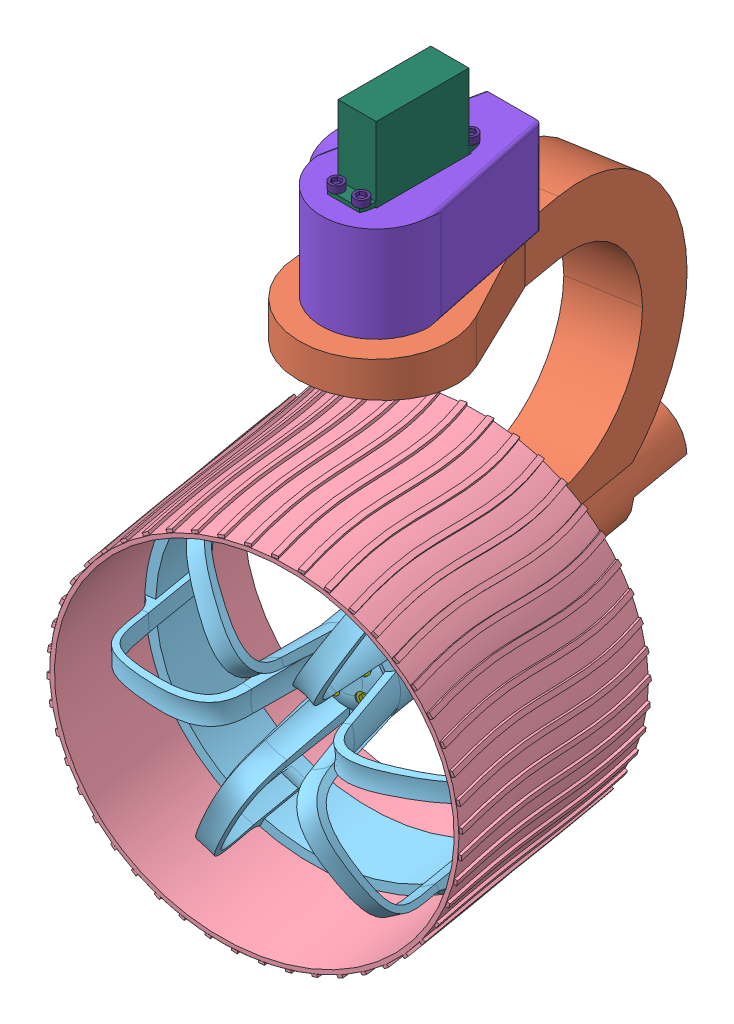
SolidWorks assembly Wheel + connector(right,front), configuration Default. Lengths in mm.
Overall size (148.6 246.82 187.43).
30 component instances, 17 part files, 54 mates.
Components (placement in the parent):
- Wheel motor(RH)-1: Wheel motor(RH) [Default] at (-243.8656 -139.499 44.1514) x (-0.875631 0.459235 0.149579) z (0.168385 0 0.985721) size (25 25 73.38)
- Wheel connector(right,front)-1: Wheel connector(right,front) [right frint (mirror)] at (-329.4884 -84.5922 3.3571) x (-0.168385 0 -0.985721) z (0.985721 0 -0.168385) size (150.03 127 55.1)
- connector to wheel(RH)-1: connector to wheel(RH) [Default] at (-239.521 -143.7607 82.6694) x (0.719368 -0.683673 -0.122885) z (-0.168385 0 -0.985721) size (25 25 12.5)
- Wheel-1: Wheel [Default] at (-237.5004 -143.7607 94.498) x (-0.032143 0.999468 0.005491) z (0.168385 0 0.985721) size (132 132 85)
  - Wheel Part-1-1: Wheel Part-1 [Default] at origin size (132 132 85)
  - Wheel Part-2-1: Wheel Part-2 [Default] at (0 0 -2) size (127 128.13 59.75)
- M3 nut-1: M3 nut [Default] at (-236.6979 -138.6522 70.7742) x (0.22394 0.973852 -0.038254) z (0.168385 0 0.985721) size (5 6.35 2.75)
- M3 nut-2: M3 nut [Default] at (-246.4509 -138.975 72.4402) x (0.673911 0.729788 -0.11512) z (0.168385 0 0.985721) size (5 6.35 2.75)
- M3 nut-3: M3 nut [Default] at (-236.3797 -148.5464 70.7198) x (0.673911 0.729788 -0.11512) z (0.168385 0 0.985721) size (5 6.35 2.75)
- M3 nut-4: M3 nut [Default] at (-246.1327 -148.8692 72.3858) x (0.943308 0.290179 -0.161139) z (0.168385 0 0.985721) size (5 6.35 2.75)
- M3 bolt for wheels(RH)-1: M3 bolt for wheels(RH) [Default] at (-242.6622 -138.975 94.6189) x (-0.910538 -0.383049 0.155542) z (-0.168385 0 -0.985721) size (5 5 25.25)
- M3 bolt for wheels(RH)-2: M3 bolt for wheels(RH) [Default] at (-242.344 -148.8692 94.5646) x (-0.910538 -0.383049 0.155542) z (-0.168385 0 -0.985721) size (5 5 25.25)
- M3 bolt for wheels(RH)-3: M3 bolt for wheels(RH) [Default] at (-232.5911 -148.5464 92.8985) x (-0.910538 -0.383049 0.155542) z (-0.168385 0 -0.985721) size (5 5 25.25)
- M3 bolt for wheels(RH)-4: M3 bolt for wheels(RH) [Default] at (-232.9093 -138.6522 92.9529) x (-0.910538 -0.383049 0.155542) z (-0.168385 0 -0.985721) size (5 5 25.25)
- Steering connector(right,front)-1: Steering connector(right,front) [RH] at (-182.0258 -27.059 85.0059) x (0 0 -1) z (1 0 0) size (70 36.07 55.83)
- Washer(M6)-1: Washer(M6) [Default] at (-237.0258 -27.559 85.0059) size (8.76 0.5 8.76)
- double row cylindrical roller bearing_is-1: double row cylindrical roller bearing_is [IS 6458 DC - 49-6-S] at (-237.0258 -22.059 85.0059) x (0.81727 0 -0.576255) z (0 -1 0) size (15 15 10)
- Steering thor joint(RH)-1: Steering thor joint(RH) [Default] at (-217.6628 -18.7982 110.524) x (0.999312 0 -0.037094) z (0 1 0) size (14.13 14.13 58.56)
  - bolt head(RH)-1: bolt head(RH) [Default] at (-18.4031 26.2188 19.7392) size (14 14 8)
  - Bogie bolt(RH)-1: Bogie bolt(RH) [Default] at (-18.4064 26.2246 14.7392) x (-1 0 0) z (0 0 -1) size (9 10.39 55.56)
  - Bolt servo connector(RH)-1: Bolt servo connector(RH) [Default] at (-18.4031 26.2188 19.7392) x (0.99996 0.008969 0) z (0 0 1) size (14 14 3)
- Servo Assembly-2: Servo Assembly [Default] at (-233.5265 1.941 84.8454) size (14 33 44) (flexible)
  - servo shaft-1: servo shaft [Default] at (-3.4993 0 0.1605) x (0.613901 0 0.789383) z (-0.789383 0 0.613901) size (5 18 5)
  - Servo motor-1: Servo motor [Default] at (-3.4993 3 -9.8395) size (14 30 44)
- Bogie nut(RH)-1: Bogie nut(RH) [Default] at (-237.0258 -41.6423 85.0059) x (0.769467 0 -0.638686) z (0.638686 0 0.769467) size (8.33 4.53 10.58)
- Bogie nut(RH)-2: Bogie nut(RH) [Default] at (-237.0258 -45.809 85.0059) x (0.61626 0 -0.787543) z (0.787543 0 0.61626) size (8.33 4.53 10.58)
- M3 bolt-1: M3 bolt [Default] at (-241.5758 10.691 95.0159) x (0.818291 0 -0.574804) z (0 -1 0) size (5 5 12.17)
- M3 bolt-2: M3 bolt [Default] at (-232.4758 10.691 95.0159) x (0.999848 0 0.017449) z (0 -1 0) size (5 5 12.17)
- M3 bolt-3: M3 bolt [Default] at (-232.4758 10.691 54.9959) x (0.999987 0 -0.005176) z (0 -1 0) size (5 5 12.17)
- M3 bolt-4: M3 bolt [Default] at (-241.5758 10.691 54.9959) x (-0.244452 0 -0.969661) z (0 -1 0) size (5 5 12.17)
Mates (geometry in assembly coordinates):
- Concentric21: concentric: cylinder of Wheel motor(RH)-1 through (-239.521 -143.7607 82.6694) axis (-0.168385 0 -0.985721) radius 2.0271; cylinder of connector to wheel(RH)-1 through (-239.5208 -143.7607 82.6704) axis (-0.168385 0 -0.985721) radius 2.025
- Coincident1: coincident: axis of connector to wheel(RH)-1 through (-234.8036 -138.6522 81.8635) axis (-0.168385 0 -0.985721); axis of M3 nut-1 through (-236.6239 -138.6522 71.2076) axis (0.168385 0 0.985721)
- Coincident2: coincident: axis of connector to wheel(RH)-1 through (-244.5565 -138.975 83.5296) axis (-0.168385 0 -0.985721); axis of M3 nut-2 through (-246.3768 -138.975 72.8736) axis (0.168385 0 0.985721)
- Coincident3: coincident: axis of connector to wheel(RH)-1 through (-234.4854 -148.5464 81.8092) axis (-0.168385 0 -0.985721); axis of M3 nut-3 through (-236.3236 -148.5464 71.0483) axis (0.168385 0 0.985721)
- Coincident4: coincident: axis of connector to wheel(RH)-1 through (-244.2383 -148.8692 83.4752) axis (-0.168385 0 -0.985721); axis of M3 nut-4 through (-246.0766 -148.8692 72.7143) axis (0.168385 0 0.985721)
- Coincident5: coincident: plane of connector to wheel(RH)-1 through (-241.2048 -143.7607 72.8122) normal (-0.168385 0 -0.985721); plane of M3 nut-1 through (-236.4874 -138.6522 72.0063) normal (0.168385 0 0.985721)
- Parallel1: parallel: plane of connector to wheel(RH)-1 through (-240.4071 -140.2917 72.6759) normal (0.22394 0.973852 -0.038254); plane of M3 nut-1 through (-238.4328 -140.7589 72.3386) normal (-0.22394 -0.973852 0.038254)
- Parallel2: parallel: plane of connector to wheel(RH)-1 through (-239.52 -141.9363 72.5244) normal (-0.673911 -0.729788 0.11512); plane of M3 nut-2 through (-243.5173 -138.1373 73.2072) normal (0.673911 0.729788 -0.11512)
- Coincident7: coincident: plane of connector to wheel(RH)-1 through (-241.2048 -143.7607 72.8122) normal (-0.168385 0 -0.985721); plane of M3 nut-2 through (-246.2404 -138.975 73.6723) normal (0.168385 0 0.985721)
- Coincident8: coincident: plane of connector to wheel(RH)-1 through (-242.0025 -147.2298 72.9484) normal (-0.22394 -0.973852 0.038254); plane of M3 nut-4 through (-243.9768 -146.7625 73.2857) normal (0.22394 0.973852 -0.038254)
- Coincident9: coincident: plane of connector to wheel(RH)-1 through (-241.2048 -143.7607 72.8122) normal (-0.168385 0 -0.985721); plane of M3 nut-4 through (-245.9222 -148.8692 73.618) normal (0.168385 0 0.985721)
- Parallel3: parallel: plane of connector to wheel(RH)-1 through (-232.9856 -145.7059 71.4081) normal (-0.959947 0.227184 0.163982); plane of M3 nut-3 through (-238.2459 -146.5728 72.3067) normal (-0.959947 0.227184 0.163982)
- Coincident10: coincident: plane of connector to wheel(RH)-1 through (-241.2048 -143.7607 72.8122) normal (-0.168385 0 -0.985721); plane of M3 nut-3 through (-236.1692 -148.5464 71.952) normal (0.168385 0 0.985721)
- Coincident11: coincident: axis of Wheel motor(RH)-1 through (-239.5437 -143.7607 82.5362) axis (-0.168385 0 -0.985721); axis of Wheel-1/Wheel Part-1-1 through (-230.344 -143.7607 136.3912) axis (-0.168385 0 -0.985721)
- Coincident13: coincident: plane of connector to wheel(RH)-1 through (-239.521 -143.7607 82.6694) normal (0.168385 0 0.985721); plane of Wheel-1/Wheel Part-2-1 through (-239.521 -143.7607 82.6694) normal (-0.168385 0 -0.985721)
- Concentric22: concentric: cylinder of connector to wheel(RH)-1 through (-244.2382 -148.8692 83.4762) axis (-0.168385 0 -0.985721) radius 1.71; cylinder of Wheel-1/Wheel Part-2-1 through (-236.071 -148.8692 131.2866) axis (-0.168385 0 -0.985721) radius 1.71
- Coincident14: coincident: axis of Wheel-1/Wheel Part-2-1 through (-242.8727 -138.975 93.3868) axis (-0.168385 0 -0.985721); axis of M3 bolt for wheels(RH)-1 through (-246.6613 -138.975 71.208) axis (0.168385 0 0.985721)
- Coincident15: coincident: plane of Wheel-1/Wheel Part-2-1 through (-242.8727 -138.975 93.3868) normal (0.168385 0 0.985721); plane of M3 bolt for wheels(RH)-1 through (-242.8727 -138.975 93.3868) normal (-0.168385 0 -0.985721)
- Coincident16: coincident: axis of Wheel-1/Wheel Part-2-1 through (-242.5545 -148.8692 93.3324) axis (-0.168385 0 -0.985721); axis of M3 bolt for wheels(RH)-2 through (-246.3432 -148.8692 71.1537) axis (0.168385 0 0.985721)
- Coincident17: coincident: plane of Wheel-1/Wheel Part-2-1 through (-237.8371 -143.7607 92.5266) normal (0.168385 0 0.985721); plane of M3 bolt for wheels(RH)-2 through (-242.5545 -148.8692 93.3324) normal (-0.168385 0 -0.985721)
- Coincident18: coincident: axis of Wheel-1/Wheel Part-2-1 through (-233.1197 -138.6522 91.7207) axis (-0.168385 0 -0.985721); axis of M3 bolt for wheels(RH)-4 through (-236.9084 -138.6522 69.542) axis (0.168385 0 0.985721)
- Coincident19: coincident: plane of Wheel-1/Wheel Part-2-1 through (-233.1197 -138.6522 91.7207) normal (0.168385 0 0.985721); plane of M3 bolt for wheels(RH)-4 through (-233.1197 -138.6522 91.7207) normal (-0.168385 0 -0.985721)
- Coincident20: coincident: axis of Wheel-1/Wheel Part-2-1 through (-232.8015 -148.5464 91.6664) axis (-0.168385 0 -0.985721); axis of M3 bolt for wheels(RH)-3 through (-236.5902 -148.5464 69.4877) axis (0.168385 0 0.985721)
- Coincident21: coincident: plane of Wheel-1/Wheel Part-2-1 through (-232.8015 -148.5464 91.6664) normal (0.168385 0 0.985721); plane of M3 bolt for wheels(RH)-3 through (-232.8015 -148.5464 91.6664) normal (-0.168385 0 -0.985721)
- Coincident22: coincident: plane of Wheel motor(RH)-1 through (-237.3798 -139.5591 82.3036) normal (0.168385 0 0.985721); plane of connector to wheel(RH)-1 through (-239.521 -143.7607 82.6694) normal (0.168385 0 0.985721)
- Coincident24: coincident: plane of Washer(M6)-1 through (-237.0258 -27.059 85.0059) normal (0 1 0); plane of double row cylindrical roller bearing_is-1 through (-235.2971 -27.059 87.4577) normal (0 -1 0)
- Concentric25: concentric: cylinder of Washer(M6)-1 through (-237.0258 -27.059 85.0059) axis (0 -1 0) radius 3; cylinder of double row cylindrical roller bearing_is-1 through (-237.0258 -92.9216 85.0059) axis (0 -1 0) radius 3
- Concentric27: concentric: cylinder of double row cylindrical roller bearing_is-1 through (-237.0258 -72.4506 85.0059) axis (0 -1 0) radius 7.5; cylinder of Steering thor joint(RH)-1/Bolt servo connector(RH)-1 through (-237.0258 1.941 85.0059) axis (0 -1 0) radius 7
- Coincident26: coincident: plane of Steering connector(right,front)-1 through (-237.0258 -27.059 85.0059) normal (0 -1 0); plane of double row cylindrical roller bearing_is-1 through (-232.7039 -27.059 91.1354) normal (0 -1 0)
- Coincident27: coincident: plane of Steering connector(right,front)-1 through (-237.0258 -7.059 85.0059) normal (0 1 0); plane of Steering thor joint(RH)-1/bolt head(RH)-1 through (-237.0258 -7.059 85.0059) normal (0 -1 0)
- Parallel15: parallel: plane of Steering connector(right,front)-1 through (-229.5258 -7.059 92.5059) normal (-1 0 0); plane of Servo Assembly-2/Servo motor-1 through (-230.0258 34.941 75.0059) normal (1 0 0)
- Concentric19: concentric: cylinder of Steering thor joint(RH)-1/Bolt servo connector(RH)-1 through (-237.0258 3.941 85.0059) axis (0 -1 0) radius 2.5; cylinder of Servo Assembly-2/servo shaft-1 through (-237.0258 19.941 85.0059) axis (0 -1 0) radius 2.5
- Coincident57: coincident: plane of Steering thor joint(RH)-1/Bolt servo connector(RH)-1 through (-237.0258 1.941 85.0059) normal (0 1 0); plane of Servo Assembly-2/servo shaft-1 through (-237.0258 1.941 85.0059) normal (0 -1 0)
- Coincident58: coincident: plane of Steering connector(right,front)-1 through (-237.0258 7.941 85.0059) normal (0 1 0); plane of Servo Assembly-2/Servo motor-1 through (-237.0258 7.941 75.0059) normal (0 -1 0)
- Concentric28: concentric: cylinder of Steering connector(right,front)-1 through (-237.0258 -17.059 85.0059) axis (0 -1 0) radius 7.5; cylinder of double row cylindrical roller bearing_is-1 through (-237.0258 -72.4506 85.0059) axis (0 -1 0) radius 7.5
- Concentric29: concentric: cylinder of Wheel connector(right,front)-1 through (-237.0258 -51.559 85.0059) axis (0 1 0) radius 3; cylinder of Steering connector(right,front)-1 through (-237.0258 -17.059 85.0059) axis (0 -1 0) radius 7.5
- Coincident60: coincident: plane of Wheel connector(right,front)-1 through (-265.4165 -27.559 -7.5879) normal (0 1 0); plane of Washer(M6)-1 through (-237.0258 -27.559 85.0059) normal (0 -1 0)
- Concentric30: concentric: cylinder of Wheel motor(RH)-1 through (-241.51 -139.5591 58.1259) axis (-0.168385 0 -0.985721) radius 12.5004; cylinder of Wheel connector(right,front)-1 through (-240.7931 -139.559 62.322) axis (-0.168385 0 -0.985721) radius 12.5
- Concentric31: concentric: cylinder of Wheel motor(RH)-1 through (-239.521 -143.7607 82.6694) axis (-0.168385 0 -0.985721) radius 2.0271; cylinder of Wheel connector(right,front)-1 through (-259.5456 -143.7607 -34.5548) axis (0.168385 0 0.985721) radius 2.435
- LimitAngle1: limit planar angle = 0.169191 rad: plane of Wheel connector(right,front)-1 through (-256.7897 -139.559 -31.3215) normal (-0.168385 0 -0.985721); plane of Steering connector(right,front)-1 through (-227.0258 7.941 35.0059) normal (0 0 -1)
- Parallel17: parallel: plane of Wheel connector(right,front)-1 through (-235.3562 -49.559 80.4936) normal (-0.769467 0 0.638686); plane of Bogie nut(RH)-1 through (-232.2833 -39.559 84.1957) normal (0.769467 0 -0.638686)
- Coincident63: coincident: plane of Wheel connector(right,front)-1 through (-240.7734 -39.559 -11.7975) normal (0 -1 0); plane of Bogie nut(RH)-1 through (-237.0258 -39.559 85.0059) normal (0 1 0)
- Concentric32: concentric: cylinder of Wheel connector(right,front)-1 through (-237.0258 -51.559 85.0059) axis (0 1 0) radius 3; axis of Bogie nut(RH)-1 through (-237.0258 -39.559 85.0059) axis (0 -1 0)
- Coincident65: coincident: axis of Bogie nut(RH)-1 through (-237.0258 -42.1977 85.0059) axis (0 -1 0); axis of Bogie nut(RH)-2 through (-237.0258 -45.233 85.0059) axis (0 1 0)
- Coincident66: coincident: plane of Bogie nut(RH)-1 through (-237.0258 -43.7257 85.0059) normal (0 -1 0); plane of Bogie nut(RH)-2 through (-237.0258 -43.7257 85.0059) normal (0 1 0)
- Coincident67: coincident: plane of Wheel motor(RH)-1 through (-240.7932 -139.5591 62.3221) normal (0.168385 0 0.985721); plane of Wheel connector(right,front)-1 through (-228.4716 -84.5922 60.2172) normal (-0.168385 0 -0.985721)
- Concentric33: concentric: cylinder of Servo Assembly-2/Servo motor-1 through (-241.5758 9.441 95.0159) axis (0 -1 0) radius 1.5; cylinder of M3 bolt-1 through (-241.5758 9.441 95.0159) axis (0 1 0) radius 2.5
- Concentric34: concentric: cylinder of Servo Assembly-2/Servo motor-1 through (-232.4758 9.441 95.0159) axis (0 -1 0) radius 1.5; cylinder of M3 bolt-2 through (-232.4758 9.441 95.0159) axis (0 1 0) radius 2.5
- Concentric35: concentric: cylinder of Servo Assembly-2/Servo motor-1 through (-241.5758 9.441 54.9959) axis (0 -1 0) radius 1.5; cylinder of M3 bolt-4 through (-241.5758 9.441 54.9959) axis (0 1 0) radius 2.5
- Concentric36: concentric: cylinder of Servo Assembly-2/Servo motor-1 through (-232.4758 9.441 54.9959) axis (0 -1 0) radius 1.5; cylinder of M3 bolt-3 through (-232.4758 9.441 54.9959) axis (0 1 0) radius 2.5
- Coincident68: coincident: plane of Servo Assembly-2/Servo motor-1 through (-237.0258 9.441 75.0059) normal (0 1 0); plane of M3 bolt-2 through (-232.4758 9.441 95.0159) normal (0 -1 0)
- Coincident69: coincident: plane of Servo Assembly-2/Servo motor-1 through (-237.0258 9.441 75.0059) normal (0 1 0); plane of M3 bolt-1 through (-241.5758 9.441 95.0159) normal (0 -1 0)
- Coincident70: coincident: plane of Servo Assembly-2/Servo motor-1 through (-237.0258 9.441 75.0059) normal (0 1 0); plane of M3 bolt-3 through (-232.4758 9.441 54.9959) normal (0 -1 0)
- Coincident71: coincident: plane of Servo Assembly-2/Servo motor-1 through (-237.0258 9.441 75.0059) normal (0 1 0); plane of M3 bolt-4 through (-241.5758 9.441 54.9959) normal (0 -1 0)
